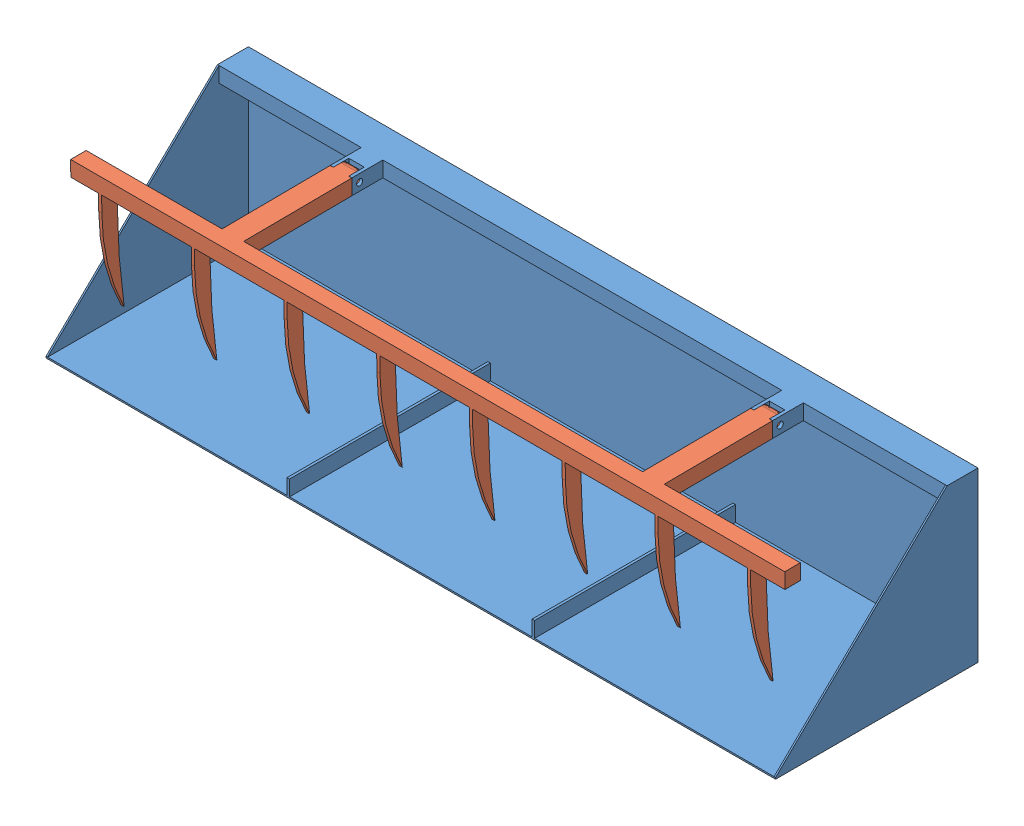
SolidWorks assembly Niederhalterschaufel, configuration Standard. Lengths in mm.
Overall size (2361 545.2 655).
2 component instances, 2 part files, 2 mates.
Components (placement in the parent):
- Schaufel-1: Schaufel [Standard] at (-1106.416 -224.8622 2038.5) size (2361 545 655)
- Niederhalter-1: Niederhalter [Standard] at (69.084 261.7753 2633.2889) x (1 0 0) z (0 -0.007913 0.999969) size (2311 400 450)
Mates (geometry in assembly coordinates):
- Konzentrisch1: concentric aligned: cylinder of Schaufel-1 through (-723.416 290.1378 2208.5) axis (1 0 0) radius 10; cylinder of Niederhalter-1 through (-710.416 290.1378 2208.5) axis (1 0 0) radius 10
- Deckungsgleich1: coincident anti-aligned: plane of Schaufel-1 through (-586.416 315.1378 2233.5) normal (-1 0 0); plane of Niederhalter-1 through (-586.416 315.3348 2183.6986) normal (1 0 0)
